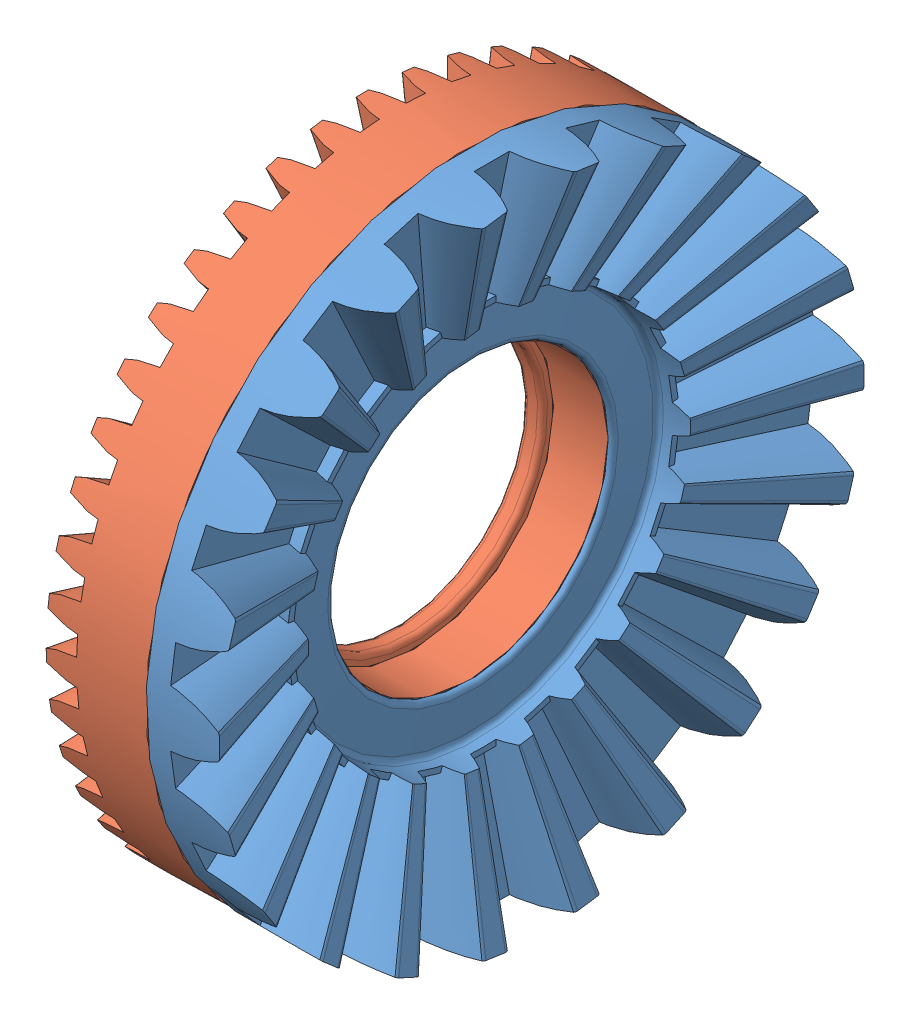
SolidWorks assembly rotor_asm240910, configuration По умолчанию. Lengths in mm.
Overall size (2148.06 197.59 275.44).
2 component instances, 2 part files, 10 mates.
Components (placement in the parent):
- gear2_240912-1: gear2_240912 [По умолчанию] at origin size (2042.38 68.15 183.13)
- my_gear3_240912-1: my_gear3_240912 [По умолчанию] at (8.5 0 0) x (-1 0 0) z (0 0.812003 -0.583653) size (404.7 85.78 181.68)
Mates (geometry in assembly coordinates):
- Концентричный1: concentric anti-aligned: cylinder of my_gear2_47-1 through (7.7082 0 0) axis (1 0 0) radius 14.1; cylinder of my_gear2_51-1 through (-10.1246 0 0) axis (-1 0 0) radius 10
- Совпадение1: coincident anti-aligned: plane of my_gear2_47-1 through (0 33.5724 0) normal (-1 0 0); plane of my_gear2_51-1 through (0 28.6516 -20.5815) normal (1 0 0)
- Концентричный2: concentric aligned: cylinder of my_gear2_51-1 through (-10.1246 0 0) axis (-1 0 0) radius 10; cylinder of road-1 through (7.1068 0 0) axis (-1 0 0) radius 10
- Совпадение2: coincident aligned: circle of my_gear2_51-1; plane of road-1 through (-2.8932 0 0) normal (-1 0 0)
- Совпадение3: coincident: plane of my_gear2_47-1 through (0 33.5724 0) normal (-1 0 0); plane of my_gear2_51a-1 through (0 9.4915 18.2074) normal (1 0 0)
- Концентричный5: concentric aligned: cylinder of my_gear2_47-1 through (7.7082 0 0) axis (-1 0 0) radius 14.1; cylinder of road-1 through (7.1068 0 0) axis (-1 0 0) radius 10
- Совпадение4: coincident aligned: circle of road-1; cylinder of my_gear3_240912-1 through (0.7918 0 0) axis (1 0 0) radius 14.1
- Концентричный6: concentric: cylinder of my_gear2_47-1 through (7.7082 0 0) axis (-1 0 0) radius 14.1; cylinder of my_gear2_51a-1 through (-1.2082 0 0) axis (-1 0 0) radius 14.1
- Совпадение5: coincident: plane of gear2_240912-1 through (7 78.5196 -39.75) normal (-1 0 0); plane of my_gear2_51a-1 through (5 19.3748 26.9551) normal (1 0 0)
- Совпадение6: coincident anti-aligned: plane of gear2_240912-1 through (7 78.5196 -39.75) normal (-1 0 0); plane of my_gear3_240912-1 through (7 -4.6914 63.7203) normal (1 0 0)
